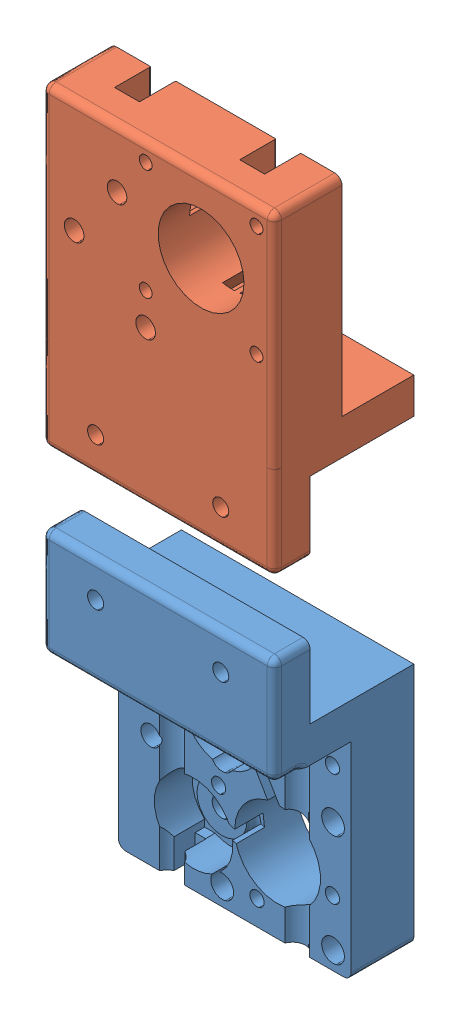
SolidWorks assembly MIRROR_MotorSupport, configuration Default. Lengths in mm.
Overall size (65.5 196 39).
2 component instances, 2 part files, 0 mates.
Components (placement in the parent):
- MotorSupport-1: MotorSupport [Default] at (33.8592 25.6056 51.6841) size (65.5 88 39)
- MirrorMotorSupport-2: MirrorMotorSupport [Default] at (33.8592 180.6056 51.6841) x (1 0 0) z (0 0 -1) size (65 88 39)
